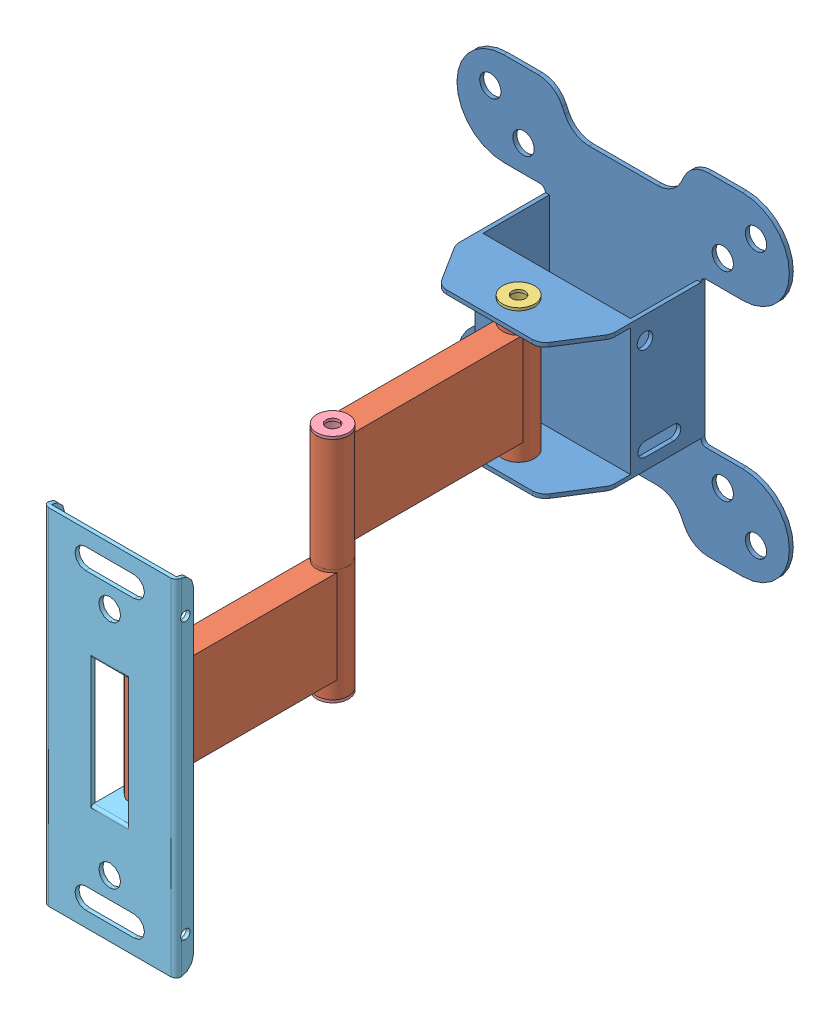
SolidWorks assembly Assem1, configuration По умолчанию. Lengths in mm.
Overall size (125.12 170.01 194.77).
7 component instances, 5 part files, 11 mates.
Components (placement in the parent):
- 1-1: 1 [Default] at (110.9235 98.4451 -18.5369) size (125.12 125.12 51.79)
- 2-1: 2 [Default] at (110.9235 98.4451 27.3244) size (12 47.88 82)
- 3-1: 3 [По умолчанию] at (110.9235 73.0068 22.3244) x (0.999806 0 0.019706) z (0 1 0) size (12 12 52.88)
- 4-1: 4 [По умолчанию] at (110.9235 32.0651 92.3244) x (1 0 -0.000268) z (0 1 0) size (12 12 86.88)
- 5-1: 5 [По умолчанию] at (110.9235 56.0016 176.2291) x (-1 0 0) z (0 0 -1) size (50 130 21.5)
- 2-2: 2 [Default] at (110.9235 56.0033 157.3244) x (-1 0 0) z (0 0 -1) size (12 47.88 82)
- 3-2: 3 [По умолчанию] at (110.9235 30.5651 162.3244) x (0.999826 0 0.01865) z (0 1 0) size (12 12 52.88)
Mates (geometry in assembly coordinates):
- Concentric1: concentric anti-aligned: cylinder of 1-1 through (110.9235 122.3833 22.3244) axis (0 1 0) radius 5; cylinder of 3-1 through (110.9235 123.8833 22.3244) axis (0 -1 0) radius 5
- Coincident1: coincident anti-aligned: plane of 1-1 through (83.1502 123.8833 7.9631) normal (0 1 0); plane of 3-1 through (110.9235 123.8833 22.3244) normal (0 -1 0)
- Concentric2: concentric anti-aligned: cylinder of 2-1 through (110.9235 74.5068 22.3244) axis (0 1 0) radius 5; cylinder of 3-1 through (110.9235 123.8833 22.3244) axis (0 -1 0) radius 5
- Coincident2: coincident anti-aligned: plane of 1-1 through (110.9235 122.3833 -18.5369) normal (0 -1 0); plane of 2-1 through (110.9235 122.3833 22.3244) normal (0 1 0)
- Concentric3: concentric anti-aligned: cylinder of 2-1 through (110.9235 74.5068 92.3244) axis (0 1 0) radius 5; cylinder of 4-1 through (110.9235 116.9451 92.3244) axis (0 -1 0) radius 5
- Coincident4: coincident anti-aligned: plane of 2-1 through (110.9235 116.9451 92.3244) normal (0 1 0); plane of 4-1 through (110.9235 116.9451 92.3244) normal (0 -1 0)
- Concentric4: concentric anti-aligned: cylinder of 4-1 through (110.9235 116.9451 92.3244) axis (0 -1 0) radius 5; cylinder of 2-2 through (110.9235 32.0651 92.3244) axis (0 1 0) radius 5
- Coincident5: coincident anti-aligned: plane of 4-1 through (110.9235 32.0651 92.3244) normal (0 1 0); plane of 2-2 through (110.9235 32.0651 92.3244) normal (0 -1 0)
- Coincident7: coincident anti-aligned: circle of 5-1; circle of 2-2
- Concentric6: concentric anti-aligned: cylinder of 2-2 through (110.9235 32.0651 162.3244) axis (0 1 0) radius 5; cylinder of 3-2 through (110.9235 81.4416 162.3244) axis (0 -1 0) radius 5
- Coincident8: coincident anti-aligned: plane of 5-1 through (103.9235 81.4416 154.7291) normal (0 1 0); plane of 3-2 through (110.9235 81.4416 162.3244) normal (0 -1 0)
